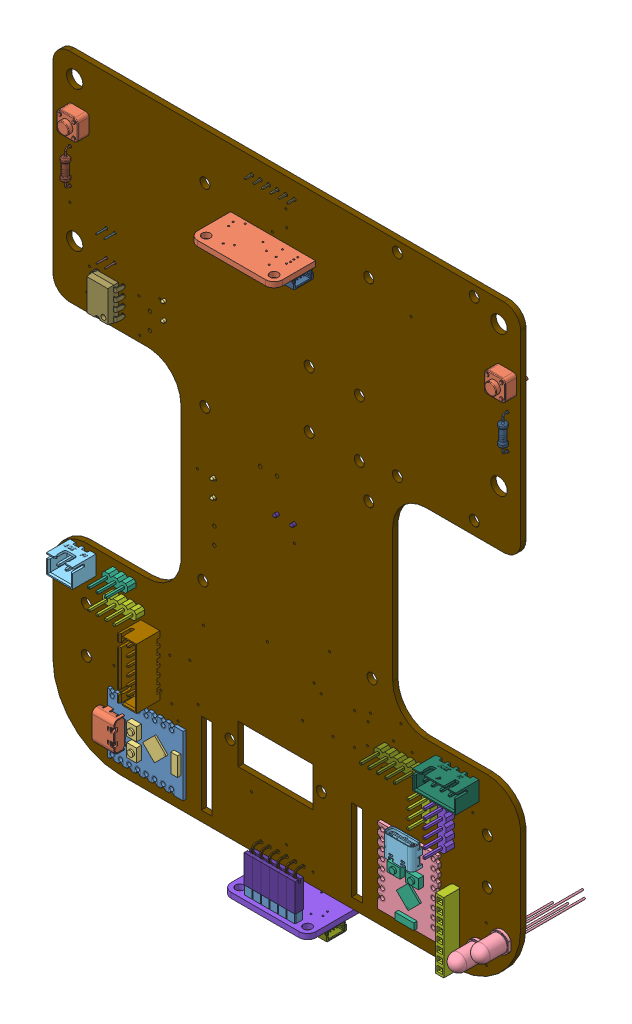
SolidWorks assembly WRO_2025 v6.step, configuration Default. Lengths in mm.
Overall size (140 193.49 37.79).
160 component instances, 72 part files, 0 mates.
Components (placement in the parent):
- Packages.step-1: Packages.step [Default] at origin size (134.83 188.87 37.79)
  - MODULE_ESP32-C3_SUPERMINI_TH.step-1: MODULE_ESP32-C3_SUPERMINI_TH.step [Default] at (28.5344 -167.434 1.57) x (0 1 0) z (0 0 1) size (18 24 4.17)
    - Board c3mini.step-1: Board c3mini.step [Default] x (-1 0 0) z (0 1 0) size (18 0.9 22.7)
    - USB C.step-1: USB C.step [Default] at (0.0001 9.275 2.4865) x (1 0 0) z (0 -1 0) size (8.97 4.07 6.75)
    - components (other)^ESP32-C3 SuperMini.step-1: components (other)^ESP32-C3 SuperMini.step [Default] x (1 0 0) z (0 -1 0) size (9.4 2 14.67)
  - MODULE_ESP32-C3_SUPERMINI_TH (1).step-1: MODULE_ESP32-C3_SUPERMINI_TH (1).step [Default] at (107.091 -163.939 1.57) size (18 24 4.17)
    - Board c3mini (1).step-1: Board c3mini (1).step [Default] x (-1 0 0) z (0 1 0) size (18 0.9 22.7)
    - USB C (1).step-1: USB C (1).step [Default] at (0.0001 9.275 2.4865) x (1 0 0) z (0 -1 0) size (8.97 4.07 6.75)
    - components (other)^ESP32-C3 SuperMini (1).step-1: components (other)^ESP32-C3 SuperMini (1).step [Default] x (1 0 0) z (0 -1 0) size (9.4 2 14.67)
  - 1X08.step-1: 1X08.step [Default] at (120.716 -168.979 1.57) x (0 1 0) z (0 0 1) size (20.82 2.5 8)
    - 8er Pin Header Female.step-1: 8er Pin Header Female.step [Default] at (15.3891 0 0) x (1 0 0) z (0 -1 0) size (20.82 8 2.5)
  - 1X06 (1).step-1: 1X06 (1).step [Default] at (65.8851 -4.8006 1.57) x (-1 0 0) z (0 0 1) size (25.4 17.45 17.78)
    - Adafruit VL6180 STEMMA QT.step.STEP.step-1: Adafruit VL6180 STEMMA QT.step.STEP.step [Default] at (0.0169 12.7201 3.5095) x (-1 0 0) z (0 1 0) size (25.4 17.78 4.55)
      - VL6180X ToF Sensor.step.STEP.step-1: VL6180X ToF Sensor.step.STEP.step [Default] at (0.025 -0.025 1.61) size (2.8 4.8 1.01)
        - VL6180X.step.STEP.step-1: VL6180X.step.STEP.step [Default] at (0 0 1) x (0 -1 0) z (1 0 0) size (4.8 1.01 2.8)
          - VL6180X_PART1.step.STEP.step-1: VL6180X_PART1.step.STEP.step [Default] at origin size (4.8 0.6 2.8)
          - VL6180X_PART2.step.STEP.step-1: VL6180X_PART2.step.STEP.step [Default] at origin size (4.8 0.1 2.8)
          - VL6180X_PART3.step.STEP.step-1: VL6180X_PART3.step.STEP.step [Default] at origin size (4.8 0.2 2.8)
          - VL6180X_PART4.step.STEP.step-1: VL6180X_PART4.step.STEP.step [Default] at origin size (4.8 0.1 2.8)
          - VL6180X_PART5.step.STEP.step-1: VL6180X_PART5.step.STEP.step [Default] at origin size (0.55 0.01 0.6)
          - VL6180X_PART5.step.STEP.step-2: VL6180X_PART5.step.STEP.step [Default] at (-0.75 0 0) size (0.55 0.01 0.6)
          - VL6180X_PART5.step.STEP.step-3: VL6180X_PART5.step.STEP.step [Default] at (-1.5 0 0) size (0.55 0.01 0.6)
          - VL6180X_PART5.step.STEP.step-4: VL6180X_PART5.step.STEP.step [Default] at (-2.25 0 0) size (0.55 0.01 0.6)
          - VL6180X_PART5.step.STEP.step-5: VL6180X_PART5.step.STEP.step [Default] at (-3 0 0) size (0.55 0.01 0.6)
          - VL6180X_PART5.step.STEP.step-6: VL6180X_PART5.step.STEP.step [Default] at (-3.75 0 0) size (0.55 0.01 0.6)
          - VL6180X_PART5.step.STEP.step-7: VL6180X_PART5.step.STEP.step [Default] at (0 0 -2.2) size (0.55 0.01 0.6)
          - VL6180X_PART5.step.STEP.step-8: VL6180X_PART5.step.STEP.step [Default] at (-0.75 0 -2.2) size (0.55 0.01 0.6)
          - VL6180X_PART5.step.STEP.step-9: VL6180X_PART5.step.STEP.step [Default] at (-1.5 0 -2.2) size (0.55 0.01 0.6)
          - VL6180X_PART5.step.STEP.step-10: VL6180X_PART5.step.STEP.step [Default] at (-2.25 0 -2.2) size (0.55 0.01 0.6)
          - VL6180X_PART5.step.STEP.step-11: VL6180X_PART5.step.STEP.step [Default] at (-3 0 -2.2) size (0.55 0.01 0.6)
          - VL6180X_PART5.step.STEP.step-12: VL6180X_PART5.step.STEP.step [Default] at (-3.75 0 -2.2) size (0.55 0.01 0.6)
          - Lens 1.step.STEP.step-1: Lens 1.step.STEP.step [Default] at origin size (0.58 0.1 0.58)
          - Lens 2.step.STEP.step-1: Lens 2.step.STEP.step [Default] at origin size (0.5 0.1 0.5)
          - Lens 3.step.STEP.step-1: Lens 3.step.STEP.step [Default] at origin size (0.3 0.1 0.3)
      - SOD-323.step.STEP.step-1: SOD-323.step.STEP.step [Default] at (4.4744 -3.0882 1.6) size (2.85 1.5 1.16)
        - SOD-323_1.step.STEP.step-1: SOD-323_1.step.STEP.step [Default] at origin size (2.85 1.5 1.16)
          - Cathode.step.STEP.step-1: Cathode.step.STEP.step [Default] at origin size (1.4 0.65 0.7)
          - Anode.step.STEP.step-1: Anode.step.STEP.step [Default] at origin size (1.4 0.65 0.7)
          - Cathode Bar.step.STEP.step-1: Cathode Bar.step.STEP.step [Default] at origin size (0.3 1.3 0.01)
          - Body.step.STEP.step-1: Body.step.STEP.step [Default] at origin size (1.95 1.5 1.05)
      - Printed Circuit Board.step.STEP.step-1: Printed Circuit Board.step.STEP.step [Default] at origin size (25.4 17.78 1.6)
      - SOT23-5.step.STEP.step-1: SOT23-5.step.STEP.step [Default] at (-5.0861 -0.1908 1.5797) x (0 -1 0) z (0 0 1) size (2.84 3.01 1.19)
      - SOT23-6.step.STEP.step-1: SOT23-6.step.STEP.step [Default] at (4.7295 -0.0372 1.1434) size (1.98 2.1 0.83)
      - YC164_RESPACK.step.STEP.step-1: YC164_RESPACK.step.STEP.step [Default] at (2.7114 2.5312 1.6) size (3.2 1.6 0.61)
      - LED 0603 single color.step.STEP.step-1: LED 0603 single color.step.STEP.step [Default] at (-9.0382 3.6666 1.6076) x (0 1 0) z (0 0 1) size (0.79 1.6 0.71)
      - CAPC-0603-T0.9-BN.step.STEP.step-1: CAPC-0603-T0.9-BN.step.STEP.step [Default] at (-2.5219 -0.3527 1.6) x (0 -1 0) z (0 0 1) size (1.7 0.9 0.9)
      - CAPC-0805-T0.95-BN.step.STEP.step-1: CAPC-0805-T0.95-BN.step.STEP.step [Default] at (-4.3183 3.0481 1.6) size (2.1 1.35 0.95)
      - CAPC-0805-T0.95-BN.step.STEP.step-2: CAPC-0805-T0.95-BN.step.STEP.step [Default] at (-5.1225 -3.3366 1.6) size (2.1 1.35 0.95)
      - RESC-0603.step.STEP.step-1: RESC-0603.step.STEP.step [Default] at (-6.8609 3.5421 1.6) x (0 -1 0) z (0 0 1) size (1.7 0.9 0.55)
      - RESC-0603.step.STEP.step-2: RESC-0603.step.STEP.step [Default] at (0.0014 -3.3485 1.6) size (1.7 0.9 0.55)
      - RESC-0603.step.STEP.step-3: RESC-0603.step.STEP.step [Default] at (0.0209 3.4129 1.6) size (1.7 0.9 0.55)
      - qwicc.step.STEP.step-1: qwicc.step.STEP.step [Default] at (-8.6284 -0.052 1.295) x (0 -1 0) z (-1 0 0) size (6 2.96 4.95)
      - qwicc.step.STEP.step-2: qwicc.step.STEP.step [Default] at (8.6675 -0.0484 1.295) x (0 1 0) z (1 0 0) size (6 2.96 4.95)
    - H254_90deg_6pin.step-1: H254_90deg_6pin.step [Default] at (5.1188 1.7801 -4.0517) x (0 1 0) z (1 0 0) size (10.36 6.14 15.24)
      - H254_90deg_3pin.step-1: H254_90deg_3pin.step [Default] at origin size (10.36 6.14 7.62)
        - FrameAndPin_H254_90deg.step-1: FrameAndPin_H254_90deg.step [Default] at origin size (10.36 6.14 2.54)
          - frame_H254.step-1: frame_H254.step [Default] at origin size (8.4 2.54 2.54)
          - pin-90deg.step-1: pin-90deg.step [Default] at (-0.0461 1.2682 1.27) x (0 0 -1) z (0.999998 -0.002105 0) size (1.95 5.07 7.58)
        - FrameAndPin_H254_90deg.step-2: FrameAndPin_H254_90deg.step [Default] at (0 0 -2.54) size (10.36 6.14 2.54)
          - frame_H254.step-1: frame_H254.step [Default] at origin size (8.4 2.54 2.54)
          - pin-90deg.step-1: pin-90deg.step [Default] at (-0.0461 1.2682 1.27) x (0 0 -1) z (0.999998 -0.002105 0) size (1.95 5.07 7.58)
        - FrameAndPin_H254_90deg.step-3: FrameAndPin_H254_90deg.step [Default] at (0 0 -5.08) size (10.36 6.14 2.54)
          - frame_H254.step-1: frame_H254.step [Default] at origin size (8.4 2.54 2.54)
          - pin-90deg.step-1: pin-90deg.step [Default] at (-0.0461 1.2682 1.27) x (0 0 -1) z (0.999998 -0.002105 0) size (1.95 5.07 7.58)
      - H254_90deg_3pin.step-2: H254_90deg_3pin.step [Default] at (0 0 -7.62) size (10.36 6.14 7.62)
        - FrameAndPin_H254_90deg.step-1: FrameAndPin_H254_90deg.step [Default] at origin size (10.36 6.14 2.54)
          - frame_H254.step-1: frame_H254.step [Default] at origin size (8.4 2.54 2.54)
          - pin-90deg.step-1: pin-90deg.step [Default] at (-0.0461 1.2682 1.27) x (0 0 -1) z (0.999998 -0.002105 0) size (1.95 5.07 7.58)
        - FrameAndPin_H254_90deg.step-2: FrameAndPin_H254_90deg.step [Default] at (0 0 -2.54) size (10.36 6.14 2.54)
          - frame_H254.step-1: frame_H254.step [Default] at origin size (8.4 2.54 2.54)
          - pin-90deg.step-1: pin-90deg.step [Default] at (-0.0461 1.2682 1.27) x (0 0 -1) z (0.999998 -0.002105 0) size (1.95 5.07 7.58)
        - FrameAndPin_H254_90deg.step-3: FrameAndPin_H254_90deg.step [Default] at (0 0 -5.08) size (10.36 6.14 2.54)
          - frame_H254.step-1: frame_H254.step [Default] at origin size (8.4 2.54 2.54)
          - pin-90deg.step-1: pin-90deg.step [Default] at (-0.0461 1.2682 1.27) x (0 0 -1) z (0.999998 -0.002105 0) size (1.95 5.07 7.58)
    - 1x06 connector.step.STEP.step-1: 1x06 connector.step.STEP.step [Default] at (7.6397 12.7201 -4.0617) x (-1 0 0) z (0 0 1) size (15.22 11.54 2.46)
  - 1X06 (3).step-1: 1X06 (3).step [Default] at (68.6537 -176.284 1.57) size (25.4 17.45 17.78)
    - Adafruit VL6180 STEMMA QT.step.STEP (1).step-1: Adafruit VL6180 STEMMA QT.step.STEP (1).step [Default] at (-0.253 -12.6587 -3.9911) x (-1 0 0) z (0 -1 0) size (25.4 17.78 4.55)
      - VL6180X ToF Sensor.step.STEP (1).step-1: VL6180X ToF Sensor.step.STEP (1).step [Default] at (0.025 -0.025 1.61) size (2.8 4.8 1.01)
        - VL6180X.step.STEP (1).step-1: VL6180X.step.STEP (1).step [Default] at (0 0 1) x (0 -1 0) z (1 0 0) size (4.8 1.01 2.8)
          - VL6180X_PART1.step.STEP (1).step-1: VL6180X_PART1.step.STEP (1).step [Default] at origin size (4.8 0.6 2.8)
          - VL6180X_PART2.step.STEP (1).step-1: VL6180X_PART2.step.STEP (1).step [Default] at origin size (4.8 0.1 2.8)
          - VL6180X_PART3.step.STEP (1).step-1: VL6180X_PART3.step.STEP (1).step [Default] at origin size (4.8 0.2 2.8)
          - VL6180X_PART4.step.STEP (1).step-1: VL6180X_PART4.step.STEP (1).step [Default] at origin size (4.8 0.1 2.8)
          - VL6180X_PART5.step.STEP (1).step-1: VL6180X_PART5.step.STEP (1).step [Default] at origin size (0.55 0.01 0.6)
          - VL6180X_PART5.step.STEP (1).step-2: VL6180X_PART5.step.STEP (1).step [Default] at (-0.75 0 0) size (0.55 0.01 0.6)
          - VL6180X_PART5.step.STEP (1).step-3: VL6180X_PART5.step.STEP (1).step [Default] at (-1.5 0 0) size (0.55 0.01 0.6)
          - VL6180X_PART5.step.STEP (1).step-4: VL6180X_PART5.step.STEP (1).step [Default] at (-2.25 0 0) size (0.55 0.01 0.6)
          - VL6180X_PART5.step.STEP (1).step-5: VL6180X_PART5.step.STEP (1).step [Default] at (-3 0 0) size (0.55 0.01 0.6)
          - VL6180X_PART5.step.STEP (1).step-6: VL6180X_PART5.step.STEP (1).step [Default] at (-3.75 0 0) size (0.55 0.01 0.6)
          - VL6180X_PART5.step.STEP (1).step-7: VL6180X_PART5.step.STEP (1).step [Default] at (0 0 -2.2) size (0.55 0.01 0.6)
          - VL6180X_PART5.step.STEP (1).step-8: VL6180X_PART5.step.STEP (1).step [Default] at (-0.75 0 -2.2) size (0.55 0.01 0.6)
          - VL6180X_PART5.step.STEP (1).step-9: VL6180X_PART5.step.STEP (1).step [Default] at (-1.5 0 -2.2) size (0.55 0.01 0.6)
          - VL6180X_PART5.step.STEP (1).step-10: VL6180X_PART5.step.STEP (1).step [Default] at (-2.25 0 -2.2) size (0.55 0.01 0.6)
          - VL6180X_PART5.step.STEP (1).step-11: VL6180X_PART5.step.STEP (1).step [Default] at (-3 0 -2.2) size (0.55 0.01 0.6)
          - VL6180X_PART5.step.STEP (1).step-12: VL6180X_PART5.step.STEP (1).step [Default] at (-3.75 0 -2.2) size (0.55 0.01 0.6)
          - Lens 1.step.STEP (1).step-1: Lens 1.step.STEP (1).step [Default] at origin size (0.58 0.1 0.58)
          - Lens 2.step.STEP (1).step-1: Lens 2.step.STEP (1).step [Default] at origin size (0.5 0.1 0.5)
          - Lens 3.step.STEP (1).step-1: Lens 3.step.STEP (1).step [Default] at origin size (0.3 0.1 0.3)
      - SOD-323.step.STEP (1).step-1: SOD-323.step.STEP (1).step [Default] at (4.4744 -3.0882 1.6) size (2.85 1.5 1.16)
        - SOD-323_1.step.STEP (1).step-1: SOD-323_1.step.STEP (1).step [Default] at origin size (2.85 1.5 1.16)
          - Cathode.step.STEP (1).step-1: Cathode.step.STEP (1).step [Default] at origin size (1.4 0.65 0.7)
          - Anode.step.STEP (1).step-1: Anode.step.STEP (1).step [Default] at origin size (1.4 0.65 0.7)
          - Cathode Bar.step.STEP (1).step-1: Cathode Bar.step.STEP (1).step [Default] at origin size (0.3 1.3 0.01)
          - Body.step.STEP (1).step-1: Body.step.STEP (1).step [Default] at origin size (1.95 1.5 1.05)
      - Printed Circuit Board.step.STEP (1).step-1: Printed Circuit Board.step.STEP (1).step [Default] at origin size (25.4 17.78 1.6)
      - SOT23-5.step.STEP (1).step-1: SOT23-5.step.STEP (1).step [Default] at (-5.0861 -0.1908 1.5797) x (0 -1 0) z (0 0 1) size (2.84 3.01 1.19)
      - SOT23-6.step.STEP (1).step-1: SOT23-6.step.STEP (1).step [Default] at (4.7295 -0.0372 1.1434) size (1.98 2.1 0.83)
      - YC164_RESPACK.step.STEP (1).step-1: YC164_RESPACK.step.STEP (1).step [Default] at (2.7114 2.5312 1.6) size (3.2 1.6 0.61)
      - LED 0603 single color.step.STEP (1).step-1: LED 0603 single color.step.STEP (1).step [Default] at (-9.0382 3.6666 1.6076) x (0 1 0) z (0 0 1) size (0.79 1.6 0.71)
      - CAPC-0603-T0.9-BN.step.STEP (1).step-1: CAPC-0603-T0.9-BN.step.STEP (1).step [Default] at (-2.5219 -0.3527 1.6) x (0 -1 0) z (0 0 1) size (1.7 0.9 0.9)
      - CAPC-0805-T0.95-BN.step.STEP (1).step-1: CAPC-0805-T0.95-BN.step.STEP (1).step [Default] at (-4.3183 3.0481 1.6) size (2.1 1.35 0.95)
      - CAPC-0805-T0.95-BN.step.STEP (1).step-2: CAPC-0805-T0.95-BN.step.STEP (1).step [Default] at (-5.1225 -3.3366 1.6) size (2.1 1.35 0.95)
      - RESC-0603.step.STEP (1).step-1: RESC-0603.step.STEP (1).step [Default] at (-6.8609 3.5421 1.6) x (0 -1 0) z (0 0 1) size (1.7 0.9 0.55)
      - RESC-0603.step.STEP (1).step-2: RESC-0603.step.STEP (1).step [Default] at (0.0014 -3.3485 1.6) size (1.7 0.9 0.55)
      - RESC-0603.step.STEP (1).step-3: RESC-0603.step.STEP (1).step [Default] at (0.0209 3.4129 1.6) size (1.7 0.9 0.55)
      - qwicc.step.STEP (1).step-1: qwicc.step.STEP (1).step [Default] at (-8.6284 -0.052 1.295) x (0 -1 0) z (-1 0 0) size (6 2.96 4.95)
      - qwicc.step.STEP (1).step-2: qwicc.step.STEP (1).step [Default] at (8.6675 -0.0484 1.295) x (0 1 0) z (1 0 0) size (6 2.96 4.95)
    - H254_90deg_6pin (1).step-1: H254_90deg_6pin (1).step [Default] at (4.8489 -1.7187 3.5701) x (0 -1 0) z (1 0 0) size (10.36 6.14 15.24)
      - H254_90deg_3pin (1).step-1: H254_90deg_3pin (1).step [Default] at origin size (10.36 6.14 7.62)
        - FrameAndPin_H254_90deg (1).step-1: FrameAndPin_H254_90deg (1).step [Default] at origin size (10.36 6.14 2.54)
          - frame_H254 (1).step-1: frame_H254 (1).step [Default] at origin size (8.4 2.54 2.54)
          - pin-90deg (1).step-1: pin-90deg (1).step [Default] at (-0.0461 1.2682 1.27) x (0 0 -1) z (0.999998 -0.002105 0) size (1.95 5.07 7.58)
        - FrameAndPin_H254_90deg (1).step-2: FrameAndPin_H254_90deg (1).step [Default] at (0 0 -2.54) size (10.36 6.14 2.54)
          - frame_H254 (1).step-1: frame_H254 (1).step [Default] at origin size (8.4 2.54 2.54)
          - pin-90deg (1).step-1: pin-90deg (1).step [Default] at (-0.0461 1.2682 1.27) x (0 0 -1) z (0.999998 -0.002105 0) size (1.95 5.07 7.58)
        - FrameAndPin_H254_90deg (1).step-3: FrameAndPin_H254_90deg (1).step [Default] at (0 0 -5.08) size (10.36 6.14 2.54)
          - frame_H254 (1).step-1: frame_H254 (1).step [Default] at origin size (8.4 2.54 2.54)
          - pin-90deg (1).step-1: pin-90deg (1).step [Default] at (-0.0461 1.2682 1.27) x (0 0 -1) z (0.999998 -0.002105 0) size (1.95 5.07 7.58)
      - H254_90deg_3pin (1).step-2: H254_90deg_3pin (1).step [Default] at (0 0 -7.62) size (10.36 6.14 7.62)
        - FrameAndPin_H254_90deg (1).step-1: FrameAndPin_H254_90deg (1).step [Default] at origin size (10.36 6.14 2.54)
          - frame_H254 (1).step-1: frame_H254 (1).step [Default] at origin size (8.4 2.54 2.54)
          - pin-90deg (1).step-1: pin-90deg (1).step [Default] at (-0.0461 1.2682 1.27) x (0 0 -1) z (0.999998 -0.002105 0) size (1.95 5.07 7.58)
        - FrameAndPin_H254_90deg (1).step-2: FrameAndPin_H254_90deg (1).step [Default] at (0 0 -2.54) size (10.36 6.14 2.54)
          - frame_H254 (1).step-1: frame_H254 (1).step [Default] at origin size (8.4 2.54 2.54)
          - pin-90deg (1).step-1: pin-90deg (1).step [Default] at (-0.0461 1.2682 1.27) x (0 0 -1) z (0.999998 -0.002105 0) size (1.95 5.07 7.58)
        - FrameAndPin_H254_90deg (1).step-3: FrameAndPin_H254_90deg (1).step [Default] at (0 0 -5.08) size (10.36 6.14 2.54)
          - frame_H254 (1).step-1: frame_H254 (1).step [Default] at origin size (8.4 2.54 2.54)
          - pin-90deg (1).step-1: pin-90deg (1).step [Default] at (-0.0461 1.2682 1.27) x (0 0 -1) z (0.999998 -0.002105 0) size (1.95 5.07 7.58)
    - 1x06 connector.step.STEP (1).step-1: 1x06 connector.step.STEP (1).step [Default] at (7.3698 -12.6587 3.5801) x (-1 0 0) z (0 0 -1) size (15.22 11.54 2.46)
  - SW_BUTT-2.step-1: SW_BUTT-2.step [Default] at (7.6911 -16.322 1.57) size (6.2 6.2 8.3)
  - SW_BUTT-2.step-2: SW_BUTT-2.step [Default] at (135.666 -19.8755 1.57) x (-1 0 0) z (0 0 1) size (6.2 6.2 8.3)
  - DBCONN-1X2.step-1: DBCONN-1X2.step [Default] at (48.1799 -91.4387 0) x (0 -1 0) z (0 0 -1) size (11.9 8.56 14.8)
  - DBCONN-1X2.step-2: DBCONN-1X2.step [Default] at (33.4905 -52.913 0) x (0 1 0) z (0 0 -1) size (11.9 8.56 14.8)
  - LED_WP7113SRD_D.step-1: LED_WP7113SRD_D.step [Default] at (134.475 -165.865 1.57) size (5.52 5.87 33.9)
  - LED_WP7113SRD_D.step-2: LED_WP7113SRD_D.step [Default] at (127.478 -171.707 1.57) x (-1 0 0) z (0 0 1) size (5.52 5.87 33.9)
  - 1X02.step-1: 1X02.step [Default] at (8.9611 -128.831 1.57) size (7.8 5.73 10)
  - 1X03.step-1: 1X03.step [Default] at (21.0718 -128.359 1.57) x (-1 0 0) z (0 0 1) size (7.62 2.54 11.34)
  - 1X04.step-1: 1X04.step [Default] at (114.097 -139.311 1.57) x (0 1 0) z (0 0 1) size (10.16 2.54 11.34)
  - 1X04.step-2: 1X04.step [Default] at (22.4155 -134.17 1.57) x (-1 0 0) z (0 0 1) size (10.16 2.54 11.34)
  - 1X06.step-1: 1X06.step [Default] at (118.842 -141.917 1.57) x (0 -1 0) z (0 0 1) size (15.24 2.54 11.34)
  - 1X06 (2).step-1: 1X06 (2).step [Default] at (28.6131 -145.71 1.57) x (0 1 0) z (0 0 1) size (17.96 5.73 10)
  - HPS58.step-1: HPS58.step [Default] at (136.03 -33.1013 1.57) x (0 1 0) z (0 0 1) size (10.51 2.32 4.51)
  - HPS58 (1).step-1: HPS58 (1).step [Default] at (5.0927 -29.6875 1.57) x (0 1 0) z (0 0 1) size (10.51 2.32 4.51)
  - TA6586-FOOTPRINT.step-1: TA6586-FOOTPRINT.step [Default] at (8.3769 -59.1261 0) x (-1 0 0) z (0 0 -1) size (9.14 9.8 7.35)
  - C2.5-3.step-1: C2.5-3.step [Default] at (17.2339 -48.1051 1.57) x (-1 0 0) z (0 0 1) size (5 5 14.57)
  - C2.5-3 (1).step-1: C2.5-3 (1).step [Default] at (17.2517 -40.3758 1.57) x (-1 0 0) z (0 0 1) size (5 5 14.57)
  - 1X05.step-1: 1X05.step [Default] at (121.072 -129.885 1.57) size (12.88 5.73 10)
  - 1X05 (1).step-1: 1X05 (1).step [Default] at (104.96 -133.238 1.57) x (-1 0 0) z (0 0 1) size (12.7 2.54 11.34)
  - DBCONN-1X2 (1).step-1: DBCONN-1X2 (1).step [Default] at (69.8068 -88.8594 1.57) size (11.9 8.56 14.8)
- Board.step-1: Board.step [Default] at origin size (140 180 1.57)
